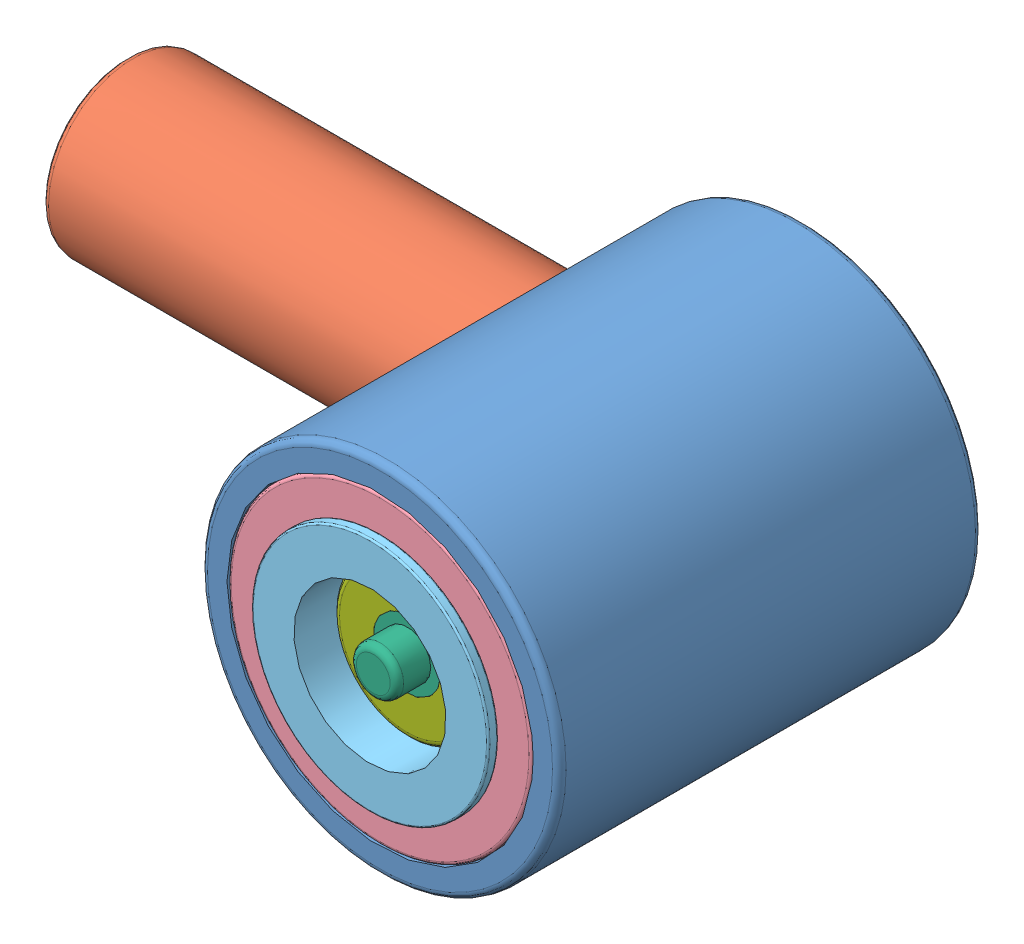
SolidWorks assembly 装配体_ABS, configuration Default. Lengths in mm.
Overall size (22.48 10.96 12.82).
7 component instances, 7 part files, 12 mates.
Components (placement in the parent):
- 充电线_ABS外壳-1: 充电线_ABS外壳 [Default] at (7.4101 7.0028 1.5709) size (10.6 10.6 12.52)
- 充电线_内膜-1: 充电线_内膜 [Default] at (7.4101 7.0028 1.5709) x (0 1 0) z (0 0 1) size (9.05 21.53 8.52)
- pcb_公座_无灯-1: pcb_公座_无灯 [Default] at (7.4101 7.0028 9.2709) x (0.620533 -0.78418 0) z (0 0 -1) size (7.8 7.8 0.9)
- 磁铁_公座-1: 磁铁_公座 [Default] at (7.4101 7.0028 10.0709) size (9 9 4)
- 铜套_公座-镀金-1: 铜套_公座-镀金 [Default] at (7.4101 7.0028 14.0709) x (0.78418 0.620533 0) z (0 0 1) size (7 7 6.8)
- 铜针_公座-1: 铜针_公座 [Default] at (7.4101 7.0028 9.3709) size (2.3 2.3 6.2)
- 胶件_公座-1: 胶件_公座 [Default] at (7.4101 7.0028 10.0709) size (7.8 7.8 4)
Mates (geometry in assembly coordinates):
- 同心1: concentric aligned: cylinder of 充电线_ABS外壳-1 through (7.4101 7.0028 14.0709) axis (0 0 -1) radius 4.525; cylinder of 充电线_内膜-1 through (7.4101 7.0028 10.0709) axis (0 0 -1) radius 4.525
- 同心3: concentric anti-aligned: cylinder of 磁铁_公座-1 through (7.4101 7.0028 14.0709) axis (0 0 -1) radius 2.85; cylinder of 铜套_公座-镀金-1 through (7.4101 7.0028 7.5709) axis (0 0 1) radius 2.75
- 重合1: coincident anti-aligned: plane of 磁铁_公座-1 through (7.4101 7.0028 14.0709) normal (0 0 1); plane of 铜套_公座-镀金-1 through (7.4101 7.0028 14.0709) normal (0 0 -1)
- 同心5: concentric aligned: cylinder of 铜套_公座-镀金-1 through (7.4101 7.0028 14.3709) axis (0 0 -1) radius 2.25; cylinder of 铜针_公座-1 through (7.4101 7.0028 13.2709) axis (0 0 -1) radius 1
- 同心6: concentric aligned: cylinder of 铜套_公座-镀金-1 through (7.4101 7.0028 14.3709) axis (0 0 -1) radius 2.25; cylinder of 胶件_公座-1 through (7.4101 7.0028 13.2709) axis (0 0 -1) radius 2.2
- 重合2: coincident anti-aligned: plane of 磁铁_公座-1 through (7.4101 7.0028 10.0709) normal (0 0 -1); plane of 胶件_公座-1 through (7.4101 7.0028 10.0709) normal (0 0 1)
- 同心7: concentric anti-aligned: cylinder of pcb_公座_无灯-1 through (7.4101 7.0028 8.4709) axis (0 0 1) radius 3.9; cylinder of 磁铁_公座-1 through (7.4101 7.0028 14.0709) axis (0 0 -1) radius 4.5
- 重合4: coincident anti-aligned: plane of pcb_公座_无灯-1 through (7.4101 7.0028 9.2709) normal (0 0 1); plane of 胶件_公座-1 through (7.4101 7.0028 9.2709) normal (0 0 -1)
- 平行1: parallel anti-aligned: plane of pcb_公座_无灯-1 through (9.5236 5.6211 8.4709) normal (-0.78418 -0.620533 0); plane of 铜套_公座-镀金-1 through (7.9198 7.4061 10.2709) normal (0.78418 0.620533 0)
- 重合8: coincident anti-aligned: plane of 铜针_公座-1 through (7.4101 7.0028 9.7709) normal (0 0 1); plane of 胶件_公座-1 through (7.4101 7.0028 9.7709) normal (0 0 -1)
- 同心8: concentric aligned: cylinder of 充电线_ABS外壳-1 through (7.4101 7.0028 14.0709) axis (0 0 -1) radius 4.525; cylinder of 磁铁_公座-1 through (7.4101 7.0028 14.0709) axis (0 0 -1) radius 4.5
- 重合9: coincident aligned: plane of 充电线_ABS外壳-1 through (7.4101 7.0028 14.0709) normal (0 0 1); plane of 磁铁_公座-1 through (7.4101 7.0028 14.0709) normal (0 0 1)
